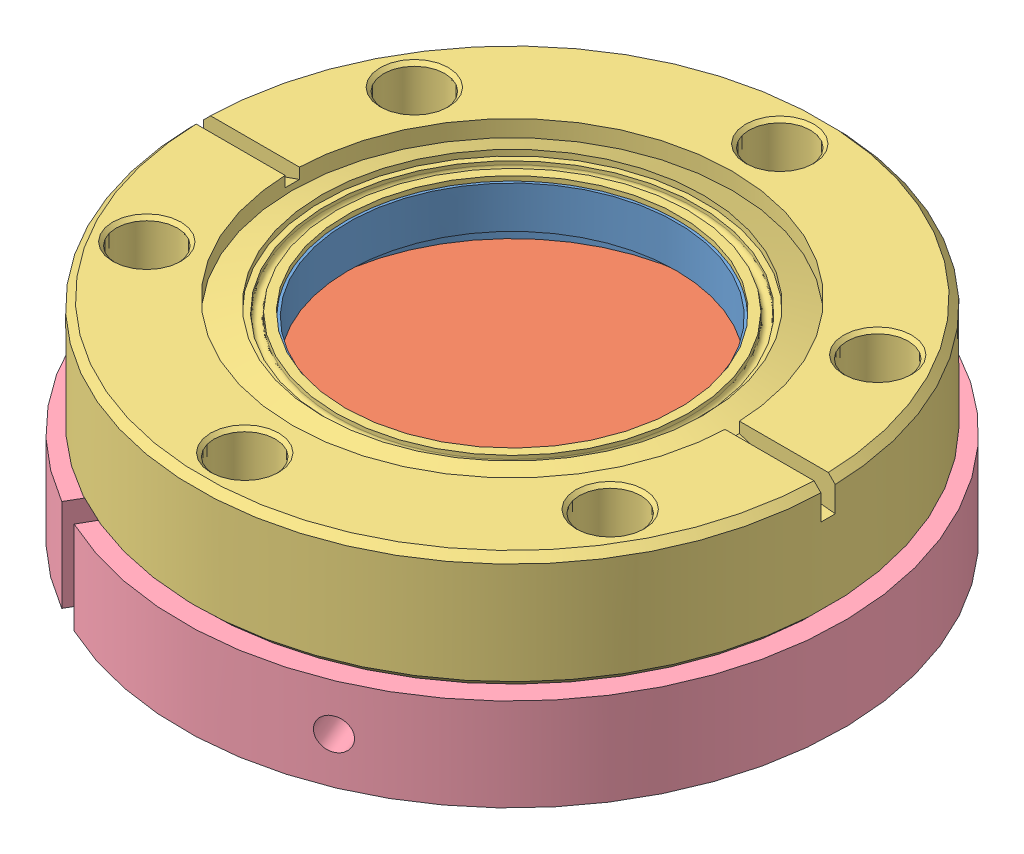
SolidWorks assembly 2.75 VP Assembly, configuration Default. Lengths in mm.
Overall size (98.89 22.87 98.89).
6 component instances, 4 part files, 3 mates.
Components (placement in the parent):
- 2.75 Window-1: 2.75 Window [Default] at (8.7044 2.1311 10.9274) size (69.34 12.71 69.34)
  - 2.75 Window P1-1: 2.75 Window P1 [Default] at (7.3044 10.0797 3.9869) size (56.02 10.92 56.02)
    - 2.75 Window P1-1-1: 2.75 Window P1-1 [Default] at (15.7152 13.9203 35.1549) size (44.88 10.92 44.88)
    - 2.75 Window P1-2-1: 2.75 Window P1-2 [Default] at (15.7152 20.9053 35.1549) x (0.940252 0 0.340481) z (0 -1 0) size (43.74 43.74 3.17)
  - 2.75 Window P2-1: 2.75 Window P2 [Default] at (23.0196 40.5099 39.1419) x (0 -1 0) z (0 0 1) size (12.71 69.34 69.34)
- Viewport Washer 2.75-1: Viewport Washer 2.75 [Default] at (31.724 29.9411 50.0692) x (0.5 0 0.866025) z (0 -1 0) size (72.39 72.39 10.16)
Mates (geometry in assembly coordinates):
- Coincident1: coincident anti-aligned: plane of 2.75 Window-1/2.75 Window P2-1 through (31.724 29.9411 50.0692) normal (0 -1 0); plane of Viewport Washer 2.75-1 through (31.724 29.9411 50.0692) normal (0 1 0)
- Concentric1: concentric anti-aligned: circle of 2.75 Window-1/2.75 Window P1-1/2.75 Window P1-1-1; circle of Viewport Washer 2.75-1
- Concentric2: concentric anti-aligned: cylinder of 2.75 Window-1/2.75 Window P2-1 through (57.1526 29.9411 35.388) axis (0 1 0) radius 3.3655; circle of Viewport Washer 2.75-1
